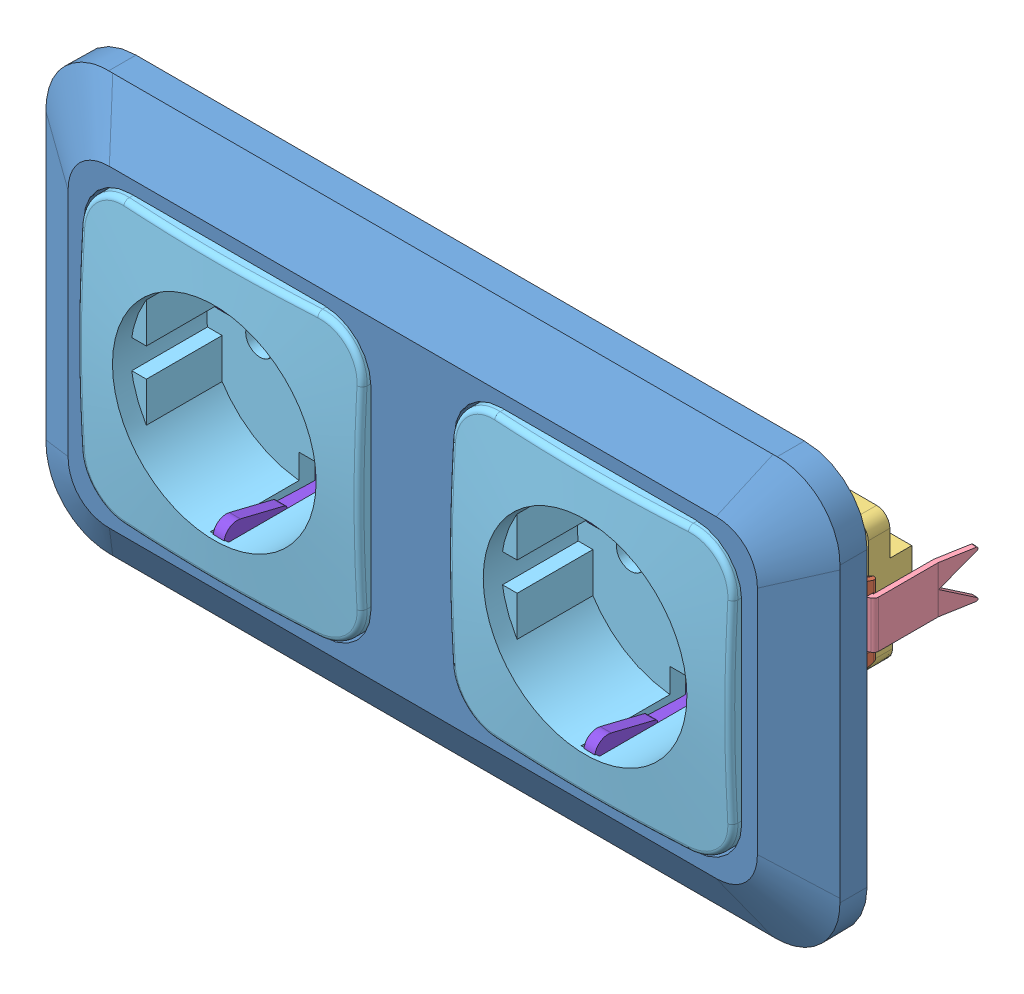
SolidWorks assembly Steckdose_2er, configuration Standard. Lengths in mm.
Overall size (152.53 80.54 48.85).
19 component instances, 8 part files, 6 mates.
Components (placement in the parent):
- Wandplatte_2er-1: Wandplatte_2er [Standard] at origin size (152.53 80.54 11)
- Steckdose-1: Steckdose [Standard] at (58.6803 128.1202 -10.7714) x (1 0 0) z (0 -1 0) size (71 48.85 71)
  - Montageplatte.02-1: Montageplatte.02 [Standard] at (-129.6803 11 128.1202) x (1 0 0) z (0 1 0) size (71 71 18.97)
  - Halter-1: Halter [Standard] at (-129.6803 11 128.1202) x (1 0 0) z (0 1 0) size (45.97 31.9 15.37)
  - Kralle.04-1: Kralle.04 [Standard] at (-126.9942 12.4168 128.1202) x (0.996195 -0.087156 0) z (0.087156 0.996195 0) size (8.78 9 23.36)
  - Kralle.04-2: Kralle.04 [Standard] at (21.6299 12.4168 26.282) x (-0.996195 -0.087156 0) z (-0.087156 0.996195 0) size (8.78 9 23.36)
  - Buchse-1: Buchse [Standard] at (-129.6803 10.7714 128.1202) x (1 0 0) z (0 1 0) size (64.03 64.03 27)
  - Stromklemme_1.02-1: Stromklemme_1.02 [Standard] at (-129.6803 11 127.9932) x (1 0 0) z (0 1 0) size (8.38 19.82 12.51)
  - Stromklemme_2.02-1: Stromklemme_2.02 [Standard] at (-129.6803 11 127.9932) x (1 0 0) z (0 1 0) size (8.38 19.82 12.51)
  - Erdleiter-1: Erdleiter [Standard] at (-129.6803 11 128.1202) x (1 0 0) z (0 1 0) size (7.24 44.01 27.12)
- Steckdose-2: Steckdose [Standard] at (129.6803 128.1202 -10.7714) x (1 0 0) z (0 -1 0) size (71 48.85 71)
  - Montageplatte.02-1: Montageplatte.02 [Standard] at (-129.6803 11 128.1202) x (1 0 0) z (0 1 0) size (71 71 18.97)
  - Halter-1: Halter [Standard] at (-129.6803 11 128.1202) x (1 0 0) z (0 1 0) size (45.97 31.9 15.37)
  - Kralle.04-1: Kralle.04 [Standard] at (-126.9942 12.4168 128.1202) x (0.996195 -0.087156 0) z (0.087156 0.996195 0) size (8.78 9 23.36)
  - Kralle.04-2: Kralle.04 [Standard] at (21.6299 12.4168 26.282) x (-0.996195 -0.087156 0) z (-0.087156 0.996195 0) size (8.78 9 23.36)
  - Buchse-1: Buchse [Standard] at (-129.6803 10.7714 128.1202) x (1 0 0) z (0 1 0) size (64.03 64.03 27)
  - Stromklemme_1.02-1: Stromklemme_1.02 [Standard] at (-129.6803 11 127.9932) x (1 0 0) z (0 1 0) size (8.38 19.82 12.51)
  - Stromklemme_2.02-1: Stromklemme_2.02 [Standard] at (-129.6803 11 127.9932) x (1 0 0) z (0 1 0) size (8.38 19.82 12.51)
  - Erdleiter-1: Erdleiter [Standard] at (-129.6803 11 128.1202) x (1 0 0) z (0 1 0) size (7.24 44.01 27.12)
Mates (geometry in assembly coordinates):
- Abstand1: distance = 0.5 mm: plane of Wandplatte_2er-1 through (-21.5019 23.4191 0) normal (0 1 0); plane of Steckdose-1/Buchse-1 through (24.4981 23.9191 -6) normal (0 -1 0)
- Abstand4: distance = 0.5 mm anti-aligned: plane of Wandplatte_2er-1 through (49.4981 23.4191 0) normal (0 1 0); plane of Steckdose-2/Buchse-1 through (95.4981 23.9191 -6) normal (0 -1 0)
- Abstand2: distance = 0.5 mm anti-aligned: plane of Wandplatte_2er-1 through (-21.5019 78.4191 0) normal (1 0 0); plane of Steckdose-1/Buchse-1 through (-21.0019 32.4191 -6) normal (-1 0 0)
- Abstand3: distance = 0.5 mm: plane of Wandplatte_2er-1 through (49.4981 78.4191 0) normal (1 0 0); plane of Steckdose-2/Buchse-1 through (49.9981 32.4191 -6) normal (-1 0 0)
- Deckungsgleich5: coincident: plane of Wandplatte_2er-1 through (0 0 -6) normal (0 0 1); plane of Steckdose-1/Buchse-1 through (5.4981 24.4191 -6) normal (0 0 -1)
- Deckungsgleich6: coincident: plane of Wandplatte_2er-1 through (0 0 -6) normal (0 0 1); plane of Steckdose-2/Buchse-1 through (76.9981 23.9191 -6) normal (0 0 -1)
